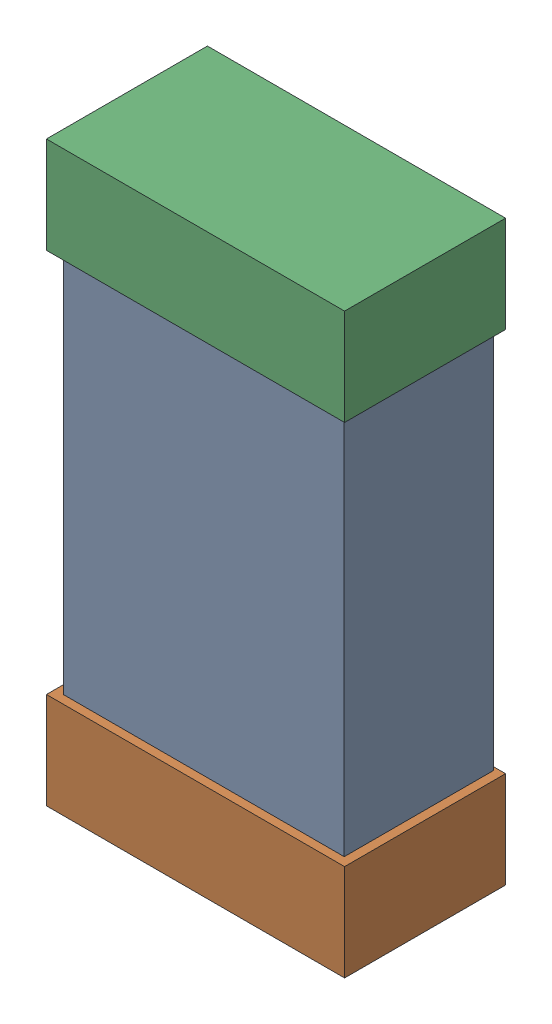
SolidWorks assembly R33, configuration Default. Lengths in mm.
Overall size (0.85 1.65 0.46).
6 component instances, 2 part files, 0 mates.
Components (placement in the parent):
- 432124816_58-1: 432124816_58 [Default] at (12.7251 23.0001 -0.8615) size (0.8 1.5 0.42)
  - Extruded (1)-1: Extruded (1) [Default] at origin size (0.8 1.5 0.42)
- 432138512_116-1: 432138512_116 [Default] at (12.7251 22.3143 -0.8715) size (0.85 0.28 0.46)
  - Extruded-1: Extruded [Default] at origin size (0.85 0.28 0.46)
- 432138512_117-1: 432138512_117 [Default] at (12.7251 23.6858 -0.8715) size (0.85 0.28 0.46)
  - Extruded-1: Extruded [Default] at origin size (0.85 0.28 0.46)
